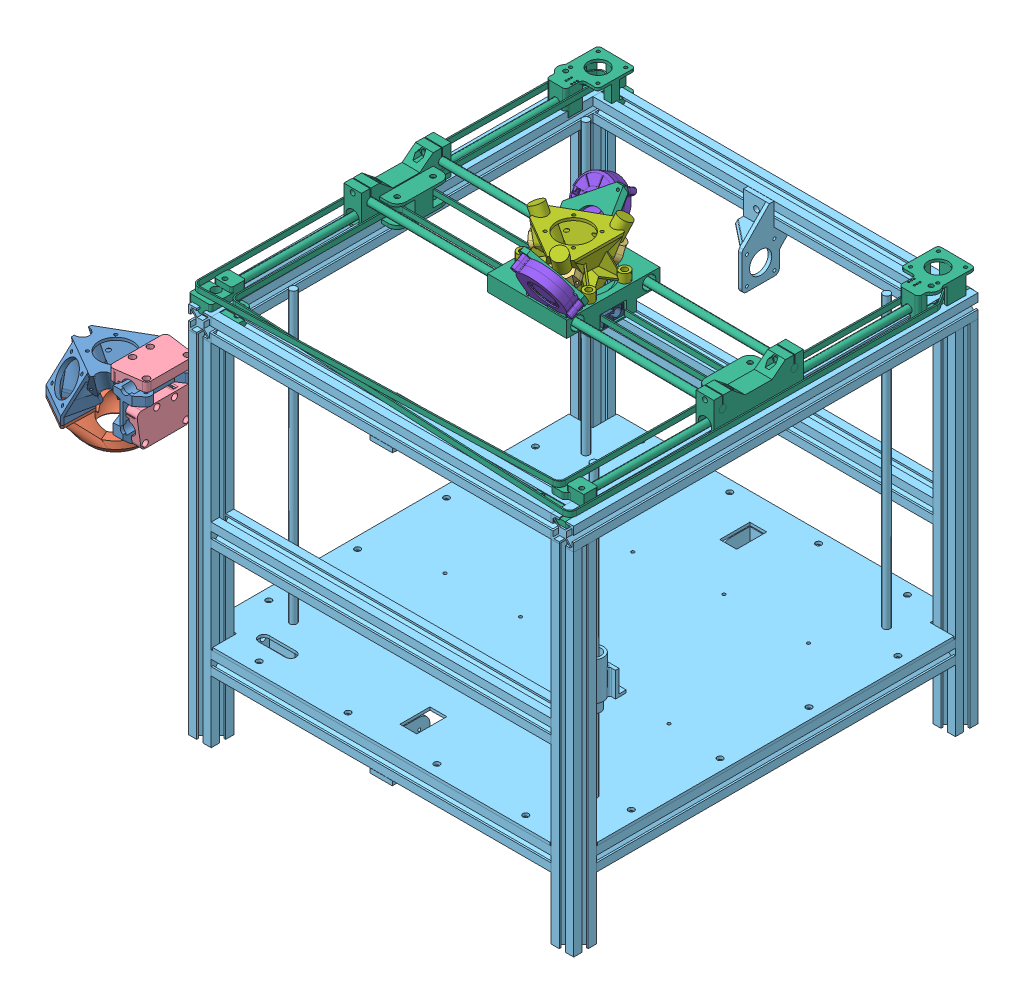
SolidWorks assembly main, configuration Default. Lengths in mm.
Overall size (591.6 502.12 484.81).
16 component instances, 10 part files, 31 mates.
Components (placement in the parent):
- diamond hotend bracket-1: diamond hotend bracket [Default] at (56.2947 30.5796 96.8627) size (108.74 80.82 111.7)
- fan_duct-1: fan_duct [Default] at (52.86 60.5796 115.176) x (-1 0 0) z (0 0 1) size (99.33 58.51 111.7)
- clamp-1: clamp [Default] at (69.0114 81.5908 74.8368) x (0.223099 0.894934 -0.386419) z (-0.447467 0.446198 0.775036) size (20 31.83 12)
- bearingClamp-1: bearingClamp [Default] at (101.2947 112.1074 96.8627) x (0 0 1) z (0 1 0) size (64 38.75 13)
- bearingClamp-2: bearingClamp [Default] at (102.3977 70.5796 96.8627) x (0 0 1) z (1 0 0) size (64 38.75 13)
- frame-1: frame [Default<As Machined>] at (169.2604 226.5326 127.8953) size (433.4 423.57 455)
- coreXY_full_gantry-1: coreXY_full_gantry [Default] at (382.4304 246.6906 -92.2183) x (0.008727 0 -0.999962) z (0.999962 0 0.008727) size (456 88.96 433)
- diamond hotend bracket_v2-1: diamond hotend bracket_v2 [Default] at (382.4304 215.6906 -92.2183) x (0.999962 0 0.008727) z (-0.008727 0 0.999962) size (93.05 88.59 88.18)
- Fan 5015-1: Fan 5015 [Default] at (354.3433 284.5012 -141.5992) x (-0.999962 0 -0.008727) z (-0.004363 -0.866025 0.499981) size (51.3 15 51.07)
- BLTouch-1: BLTouch [Default] at (343.4319 259.9906 -92.5587) x (-0.008727 0 0.999962) z (-0.999962 0 -0.008727) size (26 42.5 11.53)
- Fan 5015-2: Fan 5015 [Default] at (410.5175 284.5012 -42.8375) x (0.999962 0 0.008727) z (0.004363 -0.866025 -0.499981) size (51.3 15 51.07)
- clamp-2: clamp [Default] at (394.5149 264.912 -70.859) x (0.219718 0.894934 0.388351) z (-0.440687 0.446198 -0.778911) size (20 31.83 12)
- clamp-3: clamp [Default] at (394.8858 264.912 -113.3635) x (0.226463 0.894934 -0.384457) z (-0.454214 0.446198 0.771102) size (20 31.83 12)
- clamp-4: clamp [Default] at (357.8904 264.912 -92.4325) x (-0.446181 0.894934 -0.003894) z (0.8949 0.446198 0.00781) size (20 31.83 12)
- GT2_tensoner-1: GT2_tensoner [Default] at (421.145 234.6906 -87.1303) x (-0.008727 0 0.999962) z (-0.999962 0 -0.008727) size (12 12 13)
- GT2_tensoner-2: GT2_tensoner [Default] at (418.9496 234.6906 -96.6498) x (0.008727 0 -0.999962) z (-0.999962 0 -0.008727) size (12 12 13)
Mates (geometry in assembly coordinates):
- Coincident1: coincident anti-aligned: plane of diamond hotend bracket-1 through (56.2947 30.5796 96.8627) normal (0.447467 -0.446198 -0.775036); plane of clamp-1 through (69.0114 81.5908 74.8368) normal (-0.447467 0.446198 0.775036)
- Concentric1: concentric anti-aligned: cylinder of diamond hotend bracket-1 through (32.7834 115.8606 112.5855) axis (0.447467 -0.446198 -0.775036) radius 1.5; cylinder of clamp-1 through (65.3404 83.3959 56.1951) axis (-0.447467 0.446198 0.775036) radius 1.25
- Concentric2: concentric anti-aligned: cylinder of diamond hotend bracket-1 through (54.434 115.8606 125.0855) axis (0.447467 -0.446198 -0.775036) radius 1.5; cylinder of clamp-1 through (86.9911 83.3959 68.6951) axis (-0.447467 0.446198 0.775036) radius 1.25
- Concentric3: concentric aligned: cylinder of diamond hotend bracket-1 through (85.0447 108.5796 106.8627) axis (0 -1 0) radius 1.75; cylinder of bearingClamp-1 through (85.0447 122.1074 106.8627) axis (0 -1 0) radius 2
- Concentric4: concentric aligned: cylinder of diamond hotend bracket-1 through (85.0447 108.5796 86.8627) axis (0 -1 0) radius 1.75; cylinder of bearingClamp-1 through (85.0447 122.1074 86.8627) axis (0 -1 0) radius 2
- Concentric7: concentric anti-aligned: cylinder of diamond hotend bracket-1 through (17.4043 86.8296 86.8627) axis (1 0 0) radius 1.75; cylinder of bearingClamp-2 through (112.3977 86.8296 86.8627) axis (-1 0 0) radius 2
- Concentric8: concentric anti-aligned: cylinder of diamond hotend bracket-1 through (17.4043 86.8296 106.8627) axis (1 0 0) radius 1.75; cylinder of bearingClamp-2 through (112.3977 86.8296 106.8627) axis (-1 0 0) radius 2
- Coincident3: coincident aligned: plane of coreXY_full_gantry-1 through (382.6091 234.8677 -112.6954) normal (-0.007557 0.5 0.865992); plane of Fan 5015-1 through (377.4297 301.8218 -151.3981) normal (-0.007557 0.5 0.865992)
- Parallel1: parallel anti-aligned: line of coreXY_full_gantry-1 through (337.7157 255.6906 -125.1098) axis (0.999962 0 0.008727); line of Fan 5015-1 through (381.7314 262.5042 -128.6597) axis (-0.999962 0 -0.008727)
- Coincident7: coincident anti-aligned: plane of coreXY_full_gantry-1 through (382.4304 255.6906 -92.2183) normal (0 1 0); plane of diamond hotend bracket_v2-1 through (382.4304 255.6906 -92.2183) normal (0 -1 0)
- Coincident8: coincident anti-aligned: plane of coreXY_full_gantry-1 through (387.4311 301.8218 -33.0386) normal (-0.007557 -0.5 0.865992); plane of Fan 5015-2 through (387.4311 301.8218 -33.0386) normal (0.007557 0.5 -0.865992)
- Concentric11: concentric aligned: cylinder of coreXY_full_gantry-1 through (387.4689 304.3218 -37.3685) axis (-0.007557 -0.5 0.865992) radius 1.5; cylinder of Fan 5015-2 through (387.3782 298.3218 -26.9766) axis (-0.007557 -0.5 0.865992) radius 2.25
- Concentric12: concentric aligned: cylinder of coreXY_full_gantry-1 through (430.633 271.4128 -55.9926) axis (-0.007557 -0.5 0.865992) radius 1.5; cylinder of Fan 5015-2 through (430.5423 265.4128 -45.6007) axis (-0.007557 -0.5 0.865992) radius 2.25
- Concentric13: concentric: cylinder of coreXY_full_gantry-1 through (343.5104 245.6906 -101.5583) axis (0 1 0) radius 1.4; cylinder of BLTouch-1 through (343.5104 259.432 -101.5583) axis (0 1 0) radius 1.6
- Concentric14: concentric: cylinder of coreXY_full_gantry-1 through (343.3533 245.6906 -83.559) axis (0 1 0) radius 1.4; cylinder of BLTouch-1 through (343.3533 259.432 -83.559) axis (0 1 0) radius 1.6
- Concentric15: concentric anti-aligned: cylinder of coreXY_full_gantry-1 through (345.1063 245.6906 -112.5448) axis (0 1 0) radius 3.25; cylinder of diamond hotend bracket_v2-1 through (345.1063 265.6906 -112.5448) axis (0 -1 0) radius 3.25
- Concentric16: concentric anti-aligned: cylinder of coreXY_full_gantry-1 through (344.7573 245.6906 -72.5463) axis (0 1 0) radius 3.25; cylinder of diamond hotend bracket_v2-1 through (344.7573 265.6906 -72.5463) axis (0 -1 0) radius 3.25
- Concentric17: concentric aligned: cylinder of diamond hotend bracket_v2-1 through (403.3036 300.7093 -55.325) axis (-0.219718 -0.894934 -0.388351) radius 8; cylinder of clamp-2 through (394.5149 264.912 -70.859) axis (-0.219718 -0.894934 -0.388351) radius 8
- Coincident10: coincident anti-aligned: plane of diamond hotend bracket_v2-1 through (382.4304 215.6906 -92.2183) normal (0.440687 -0.446198 0.778911); plane of clamp-2 through (394.5149 264.912 -70.859) normal (-0.440687 0.446198 -0.778911)
- Coincident11: coincident anti-aligned: plane of diamond hotend bracket_v2-1 through (394.5149 264.912 -70.859) normal (0.219718 0.894934 0.388351); plane of clamp-2 through (404.9592 264.912 -76.7681) normal (-0.219718 -0.894934 -0.388351)
- Concentric18: concentric aligned: cylinder of diamond hotend bracket_v2-1 through (340.0432 300.7093 -92.5882) axis (0.446181 -0.894934 0.003894) radius 8; cylinder of clamp-4 through (357.8904 264.912 -92.4325) axis (0.446181 -0.894934 0.003894) radius 8
- Coincident12: coincident anti-aligned: plane of diamond hotend bracket_v2-1 through (382.4304 215.6906 -92.2183) normal (-0.8949 -0.446198 -0.00781); plane of clamp-4 through (357.8904 264.912 -92.4325) normal (0.8949 0.446198 0.00781)
- Coincident13: coincident anti-aligned: plane of diamond hotend bracket_v2-1 through (357.8904 264.912 -92.4325) normal (-0.446181 0.894934 -0.003894); plane of clamp-4 through (357.7857 264.912 -80.4329) normal (0.446181 -0.894934 0.003894)
- Concentric19: concentric aligned: cylinder of diamond hotend bracket_v2-1 through (403.9443 300.7093 -128.7417) axis (-0.226463 -0.894934 0.384457) radius 8; cylinder of clamp-3 through (394.8858 264.912 -113.3635) axis (-0.226463 -0.894934 0.384457) radius 8
- Coincident14: coincident anti-aligned: plane of diamond hotend bracket_v2-1 through (382.4304 215.6906 -92.2183) normal (0.454214 -0.446198 -0.771102); plane of clamp-3 through (394.8858 264.912 -113.3635) normal (-0.454214 0.446198 0.771102)
- Coincident15: coincident anti-aligned: plane of diamond hotend bracket_v2-1 through (394.8858 264.912 -113.3635) normal (0.226463 0.894934 -0.384457); plane of clamp-3 through (384.5463 264.912 -119.4539) normal (-0.226463 -0.894934 0.384457)
- Concentric20: concentric aligned: cylinder of coreXY_full_gantry-1 through (165.8962 234.6906 -89.3578) axis (0.999962 0 0.008727) radius 2; cylinder of GT2_tensoner-1 through (416.1452 234.6906 -87.1739) axis (0.999962 0 0.008727) radius 2.875
- Parallel2: parallel aligned: plane of coreXY_full_gantry-1 through (369.1969 227.0906 -107.1844) normal (0 1 0); plane of GT2_tensoner-1 through (416.1452 240.6906 -87.1739) normal (0 1 0)
- Concentric21: concentric aligned: cylinder of coreXY_full_gantry-1 through (165.9791 234.6906 -98.8574) axis (0.999962 0 0.008727) radius 2; cylinder of GT2_tensoner-2 through (413.9497 234.6906 -96.6934) axis (0.999962 0 0.008727) radius 2.875
- Parallel3: parallel anti-aligned: plane of coreXY_full_gantry-1 through (369.1969 227.0906 -107.1844) normal (0 1 0); plane of GT2_tensoner-2 through (413.9497 228.6906 -96.6934) normal (0 -1 0)
- Coincident19: coincident anti-aligned: plane of coreXY_full_gantry-1 through (382.4304 257.6906 -92.2183) normal (0 1 0); plane of BLTouch-1 through (343.3533 257.6906 -83.559) normal (0 -1 0)
